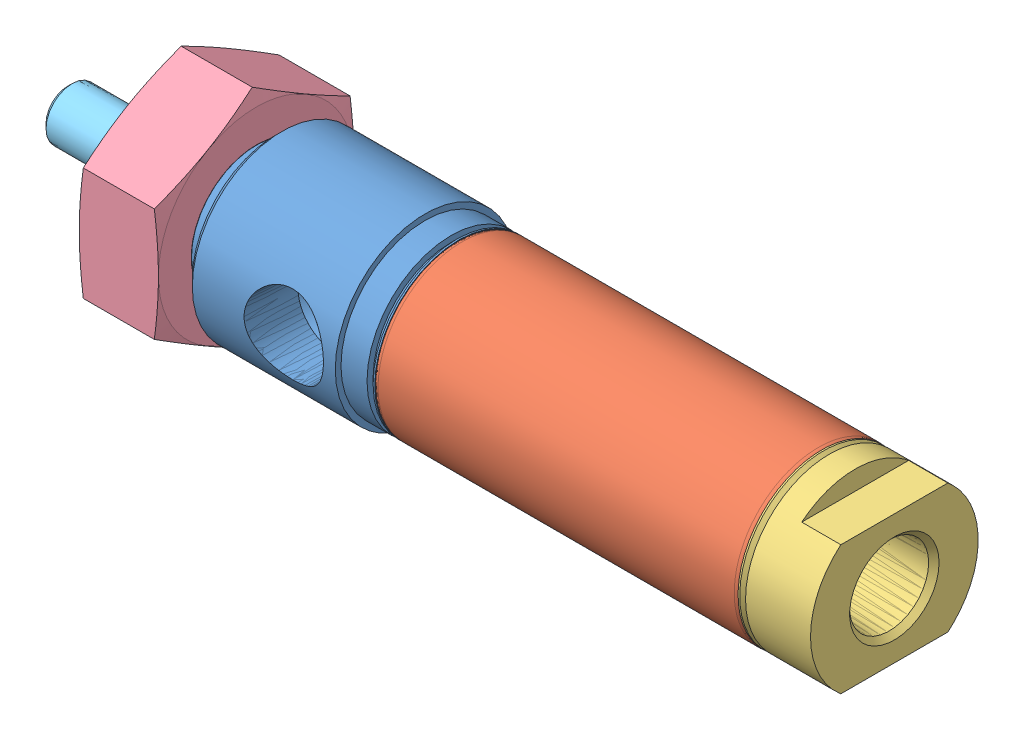
SolidWorks assembly 040_5-D, configuration Default. Lengths in mm.
Overall size (100.84 27.57 23.88).
6 component instances, 6 part files, 14 mates.
Components (placement in the parent):
- 040_5-DC0000_0_dummy-1: 040_5-DC0000_0_dummy [Default] at origin
- 04R000-0_rod_guide-1: 04R000-0_rod_guide [Default] at origin size (40.49 21.91 21.91)
- 04R-1_75650C-1: 04R-1_75650C [Default] at (34.8361 0 0) size (45.97 20.51 20.51)
- 040000_rear_head-1: 040000_rear_head [Default] at (74.6506 0 0) size (13.49 20.45 20.45)
- D-9-1: D-9 [Default] at (10.3124 0 0) x (0 0 -1) z (1 0 0) size (23.88 27.57 9.65)
- C-040_5-D0_rod-1: C-040_5-D0_rod [Default] at origin size (87.35 19.24 19.24)
Mates (geometry in assembly coordinates):
- Distance2: distance = 0 mm aligned: plane of 04R000-0_rod_guide-1 through (0 0 0) normal (1 0 0); plane of 040_5-DC0000_0_dummy-1 through (0 0 0) normal (1 0 0)
- Coincident1: coincident aligned: line of 040_5-DC0000_0_dummy-1 through (80.9 0 0) axis (-1 0 0); line of 04R000-0_rod_guide-1 through (80.9 0 0) axis (-1 0 0)
- Angle3: planar angle = 0 rad aligned: plane of 04R000-0_rod_guide-1 through (0 0 0) normal (0 0 -1); plane of 040_5-DC0000_0_dummy-1 through (0 0 0) normal (0 0 -1)
- Distance4: distance = 0 mm aligned: plane of 04R-1_75650C-1 through (34.8361 0 0) normal (1 0 0); plane of 04R000-0_rod_guide-1 through (34.8361 0 0) normal (1 0 0)
- Coincident2: coincident aligned: line of 04R000-0_rod_guide-1 through (80.9 0 0) axis (-1 0 0); line of 04R-1_75650C-1 through (115.7361 0 0) axis (-1 0 0)
- Angle6: planar angle = 0 rad aligned: plane of 04R-1_75650C-1 through (34.8361 0 0) normal (0 0 -1); plane of 04R000-0_rod_guide-1 through (0 0 0) normal (0 0 -1)
- Distance6: distance = 0 mm aligned: plane of 040000_rear_head-1 through (79.4512 0 0) normal (1 0 0); plane of 04R-1_75650C-1 through (79.4512 0 0) normal (1 0 0)
- Coincident3: coincident aligned: line of 04R-1_75650C-1 through (115.7361 0 0) axis (-1 0 0); line of 040000_rear_head-1 through (155.5506 0 0) axis (-1 0 0)
- Angle9: planar angle = 0 rad aligned: plane of 040000_rear_head-1 through (74.6506 0 0) normal (0 0 -1); plane of 04R-1_75650C-1 through (34.8361 0 0) normal (0 0 -1)
- Distance8: distance = 0 mm aligned: plane of D-9-1 through (10.3124 0 0) normal (1 0 0); plane of 04R000-0_rod_guide-1 through (10.3124 0 0) normal (1 0 0)
- Coincident4: coincident aligned: line of 04R000-0_rod_guide-1 through (80.9 0 0) axis (-1 0 0); line of D-9-1 through (91.2124 0 0) axis (-1 0 0)
- Angle12: planar angle = 0 rad aligned: plane of D-9-1 through (10.3124 0 0) normal (0 0 -1); plane of 04R000-0_rod_guide-1 through (0 0 0) normal (0 0 -1)
- LimitDistance2: limit distance = 0 mm aligned: plane of C-040_5-D0_rod-1 through (0 0 0) normal (1 0 0); plane of 04R000-0_rod_guide-1 through (0 0 0) normal (1 0 0)
- Coincident5: coincident aligned: line of 04R000-0_rod_guide-1 through (80.9 0 0) axis (-1 0 0); line of C-040_5-D0_rod-1 through (80.9 0 0) axis (-1 0 0)
